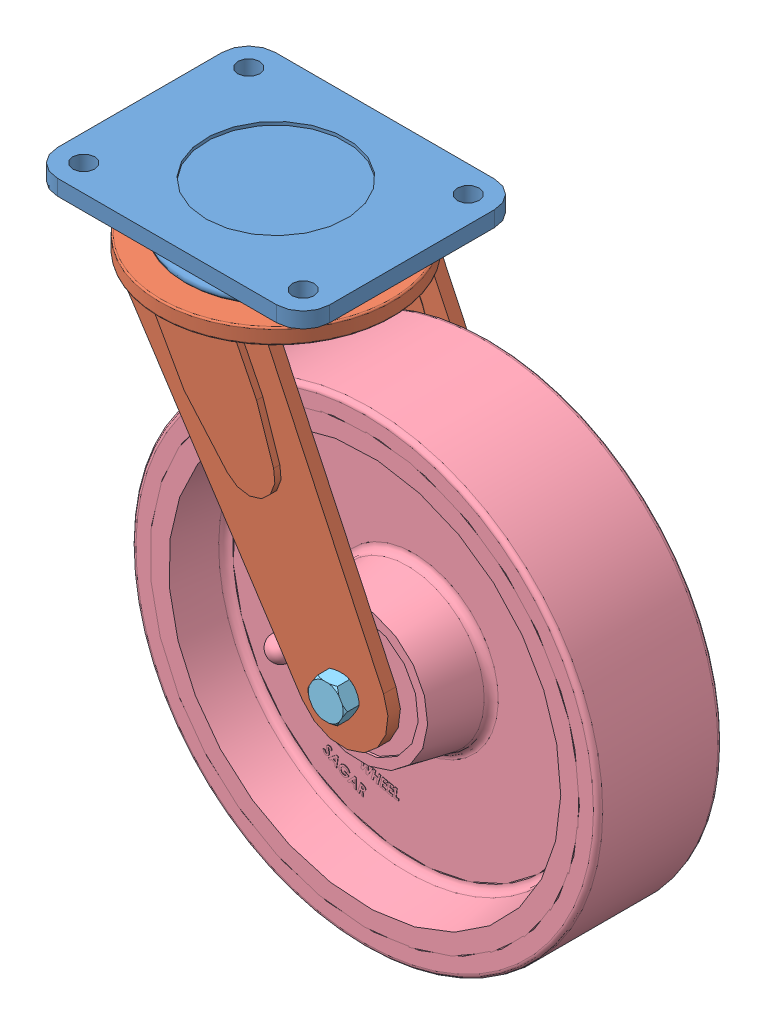
SolidWorks assembly Assem1, configuration Default. Lengths in mm.
Overall size (377.56 398.78 150).
6 component instances, 5 part files, 11 mates.
Components (placement in the parent):
- 1.mounting wheel-1: 1.mounting wheel [Default] at (82.3824 111.2957 123.6465) size (175 55 140)
- 3.horn-1: 3.horn [Default] at (82.3824 81.2957 123.6465) x (-1 0 0) z (0 0 -1) size (202 210 150)
- 2.nut-1: 2.nut [Default] at (82.3824 71.2957 123.6465) x (0.982621 0 0.185622) z (-0.185622 0 0.982621) size (22 10 25.4)
- 5.wheel-1: 5.wheel [Default] at (179.3824 -88.7043 123.6465) x (0.951801 0.306715 0) z (0 0 -1) size (300 300 87)
- 2.nut-2: 2.nut [Default] at (179.3824 -88.7043 68.6465) x (-0.087845 0.996134 0) z (-0.996134 -0.087845 0) size (22 10 25.4)
- 4.bplt-1: 4.bplt [Default] at (179.3824 -88.7043 178.6465) x (0 1 0) z (1 0 0) size (22 136 25.4)
Mates (geometry in assembly coordinates):
- Concentric1: concentric anti-aligned: cylinder of 1.mounting wheel-1 through (82.3824 91.2957 123.6465) axis (0 1 0) radius 56; cylinder of 3.horn-1 through (82.3824 91.2957 123.6465) axis (0 -1 0) radius 75
- Coincident1: coincident anti-aligned: plane of 1.mounting wheel-1 through (82.3824 91.2957 123.6465) normal (0 -1 0); plane of 3.horn-1 through (82.3824 91.2957 123.6465) normal (0 1 0)
- Concentric2: concentric aligned: cylinder of 1.mounting wheel-1 through (82.3824 66.2957 123.6465) axis (0 1 0) radius 7.5; cylinder of 2.nut-1 through (82.3824 71.2957 123.6465) axis (0 1 0) radius 7.5
- Coincident2: coincident anti-aligned: plane of 3.horn-1 through (82.3824 81.2957 123.6465) normal (0 -1 0); plane of 2.nut-1 through (82.3824 81.2957 123.6465) normal (0 1 0)
- Width1: width anti-aligned: plane of 5.wheel-1; plane of 5.wheel-1; plane of 3.horn-1; plane of 3.horn-1
- Concentric3: concentric anti-aligned: cylinder of 3.horn-1 through (183.7947 -88.7043 170.0098) axis (-0.086894 0 -0.996218) radius 7.5; cylinder of 5.wheel-1 through (175.2356 -88.7043 71.8823) axis (0.086894 0 0.996218) radius 7.5
- Concentric4: concentric aligned: cylinder of 5.wheel-1 through (175.2356 -88.7043 71.8823) axis (0.086894 0 0.996218) radius 7.5; cylinder of 4.bplt-1 through (172.846 -88.7043 44.4864) axis (0.086894 0 0.996218) radius 7.5
- Coincident3: coincident anti-aligned: plane of 3.horn-1; plane of 4.bplt-1
- Concentric5: concentric anti-aligned: cylinder of 2.nut-2 through (174.2363 -88.7043 60.4258) axis (-0.086894 0 -0.996218) radius 7.5; cylinder of 4.bplt-1 through (172.846 -88.7043 44.4864) axis (0.086894 0 0.996218) radius 7.5
- Coincident5: coincident anti-aligned: plane of 3.horn-1; plane of 2.nut-2
- Parallel1: parallel aligned: plane of 1.mounting wheel-1 through (11.8824 121.2957 193.6465) normal (0 0 1); plane of 3.horn-1 through (179.3824 -88.7043 178.6465) normal (0 0 1)
